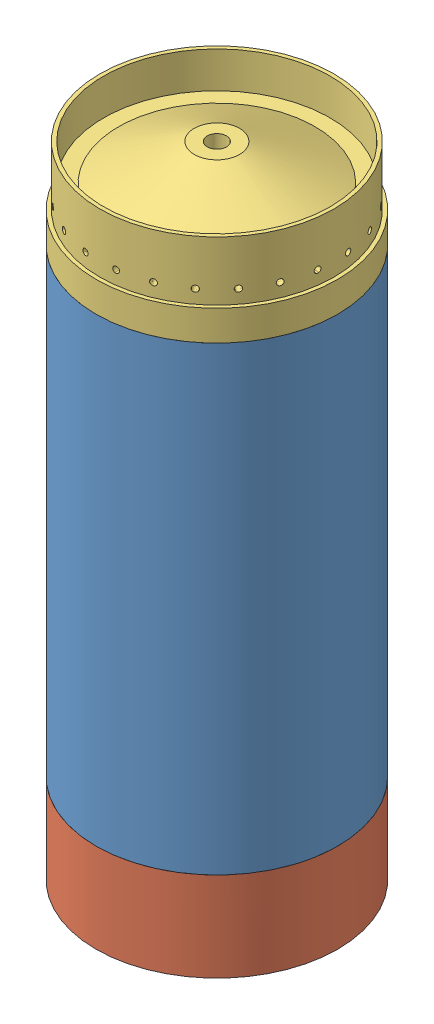
SolidWorks assembly Fuel_TankV2, configuration Default. Lengths in mm.
Overall size (246.64 537.53 246.64).
4 component instances, 4 part files, 10 mates.
Components (placement in the parent):
- FuelTankCylinder-1: FuelTankCylinder [Default] at (0 75.0887 0) x (0 1 0) z (-0.969773 0 -0.244009) size (387.35 203.2 203.2)
- LT-B-BULKHEADv4-1: LT-B-BULKHEADv4 [Default] at (0 37.5444 37.5444) x (-1 0 0) z (0 0 1) size (203.2 75.09 203.2)
- IT-B-Bulkhead-1: IT-B-Bulkhead [Default] at (0 499.9831 37.5444) size (203.2 75.09 203.2)
- Arbitrary Kerosene in Fuel Tank-1: Arbitrary Kerosene in Fuel Tank [Default] at (0 75.0887 0) x (0.944559 0 -0.328341) z (0.328341 0 0.944559) size (190.5 451.1 190.5)
Mates (geometry in assembly coordinates):
- Coincident1: coincident anti-aligned: plane of LT-B-BULKHEADv4-1 through (0 0 0) normal (0 -1 0)
- Concentric2: concentric aligned: circle of FuelTankCylinder-1; circle of LT-B-BULKHEADv4-1
- Coincident4: coincident anti-aligned: plane of FuelTankCylinder-1 through (0 75.0887 0) normal (0 -1 0); plane of LT-B-BULKHEADv4-1 through (0 75.0887 0) normal (0 1 0)
- Concentric4: concentric aligned: cylinder of LT-B-BULKHEADv4-1 through (0 75.0887 0) axis (0 1 0) radius 8.255
- Concentric5: concentric aligned: cylinder of FuelTankCylinder-1 through (0 462.4388 0) axis (0 -1 0) radius 101.6; cylinder of IT-B-Bulkhead-1 through (0 462.4388 0) axis (0 -1 0) radius 101.6
- Coincident5: coincident anti-aligned: plane of FuelTankCylinder-1 through (0 462.4388 0) normal (0 1 0); plane of IT-B-Bulkhead-1 through (0 462.4388 0) normal (0 -1 0)
- Coincident6: coincident anti-aligned: plane of LT-B-BULKHEADv4-1 through (0 37.5444 37.5444) normal (-1 0 0)
- Coincident7: coincident aligned: plane of IT-B-Bulkhead-1 through (0 499.9831 37.5444) normal (1 0 0)
- Concentric6: concentric aligned: cylinder of FuelTankCylinder-1 through (0 462.4388 0) axis (0 -1 0) radius 95.25; cylinder of Arbitrary Kerosene in Fuel Tank-1 through (0 462.4388 0) axis (0 -1 0) radius 95.25
- Coincident8: coincident anti-aligned: circle of LT-B-BULKHEADv4-1; circle of Arbitrary Kerosene in Fuel Tank-1
